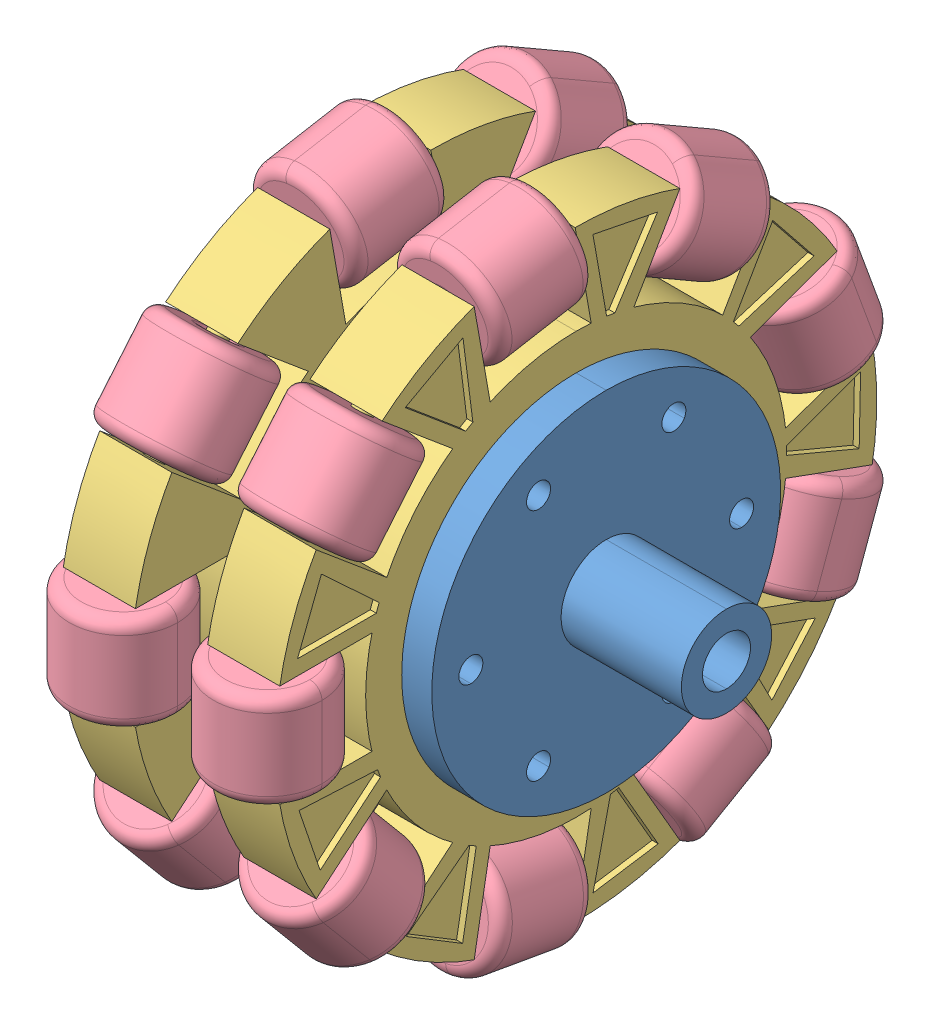
SolidWorks assembly omni wheel with hub, configuration Default. Lengths in mm.
Overall size (67.69 113.32 110.39).
26 component instances, 4 part files, 0 mates.
Components (placement in the parent):
- omni wheel with hub.igs-1: omni wheel with hub.igs [Default] at origin size (67.69 113.32 110.39)
  - Part1.1.2.3.2.igs-1: Part1.1.2.3.2.igs [Default] at (11 0 0) size (26.01 58.01 58.01)
  - Product1.1.2.igs-1: Product1.1.2.igs [Default] at origin size (49.36 113.32 110.39)
    - Part1.1.2.1.2.igs-1: Part1.1.2.1.2.igs [Default] at (-12 0 0) size (12.01 58.01 58.01)
    - Product1.1.2.6.igs-1: Product1.1.2.6.igs [Default] at origin size (25.36 112.48 110.39)
      - Part1.4.igs-1: Part1.4.igs [Default] at origin size (17.06 100.02 99.39)
      - Part1.1.3.igs-1: Part1.1.3.igs [Default] at (6 -8.0271 45.2675) x (0 1 0) z (0 0 1) size (16.01 18 18)
      - Part1.1.3.igs-2: Part1.1.3.igs [Default] at (6 22.9483 39.8366) x (0 0.766044 -0.642788) z (0.642788 0.492404 0.586824) size (16.01 18 18)
      - Part1.1.3.igs-3: Part1.1.3.igs [Default] at (6 43.1859 15.7657) x (0 0.173648 -0.984808) z (0.984808 0.17101 0.030154) size (16.01 18 18)
      - Part1.1.3.igs-4: Part1.1.3.igs [Default] at (6 43.3414 -15.4656) x (0 -0.5 -0.866025) z (0.866025 -0.433013 0.25) size (16.01 18 18)
      - Part1.1.3.igs-5: Part1.1.3.igs [Default] at (6 23.0254 -39.7921) x (0 -0.939693 -0.34202) z (0.34202 -0.321394 0.883022) size (16.01 18 18)
      - Part1.1.3.igs-6: Part1.1.3.igs [Default] at (6 -7.9394 -45.283) x (0 -0.939693 0.34202) z (-0.34202 0.321394 0.883022) size (16.01 18 18)
      - Part1.1.3.igs-7: Part1.1.3.igs [Default] at (6 -35.1893 -29.5854) x (0 -0.5 0.866025) z (-0.866025 0.433013 0.25) size (16.01 18 18)
      - Part1.1.3.igs-8: Part1.1.3.igs [Default] at (6 -45.9737 -0.0445) x (0 0.173648 0.984808) z (-0.984808 -0.17101 0.030154) size (16.01 18 18)
      - Part1.1.3.igs-9: Part1.1.3.igs [Default] at (6 -35.2465 29.5172) x (0 0.766044 0.642788) z (-0.642788 -0.492404 0.586824) size (16.01 18 18)
    - Product1.1.2.6.igs-2: Product1.1.2.6.igs [Default] at (-12 -0.8564 0) x (-1 0 0) z (0 0 1) size (25.36 112.48 110.39)
      - Part1.4.igs-1: Part1.4.igs [Default] at origin size (17.06 100.02 99.39)
      - Part1.1.3.igs-1: Part1.1.3.igs [Default] at (6 -8.0271 45.2675) x (0 1 0) z (0 0 1) size (16.01 18 18)
      - Part1.1.3.igs-2: Part1.1.3.igs [Default] at (6 22.9483 39.8366) x (0 0.766044 -0.642788) z (0.642788 0.492404 0.586824) size (16.01 18 18)
      - Part1.1.3.igs-3: Part1.1.3.igs [Default] at (6 43.1859 15.7657) x (0 0.173648 -0.984808) z (0.984808 0.17101 0.030154) size (16.01 18 18)
      - Part1.1.3.igs-4: Part1.1.3.igs [Default] at (6 43.3414 -15.4656) x (0 -0.5 -0.866025) z (0.866025 -0.433013 0.25) size (16.01 18 18)
      - Part1.1.3.igs-5: Part1.1.3.igs [Default] at (6 23.0254 -39.7921) x (0 -0.939693 -0.34202) z (0.34202 -0.321394 0.883022) size (16.01 18 18)
      - Part1.1.3.igs-6: Part1.1.3.igs [Default] at (6 -7.9394 -45.283) x (0 -0.939693 0.34202) z (-0.34202 0.321394 0.883022) size (16.01 18 18)
      - Part1.1.3.igs-7: Part1.1.3.igs [Default] at (6 -35.1893 -29.5854) x (0 -0.5 0.866025) z (-0.866025 0.433013 0.25) size (16.01 18 18)
      - Part1.1.3.igs-8: Part1.1.3.igs [Default] at (6 -45.9737 -0.0445) x (0 0.173648 0.984808) z (-0.984808 -0.17101 0.030154) size (16.01 18 18)
      - Part1.1.3.igs-9: Part1.1.3.igs [Default] at (6 -35.2465 29.5172) x (0 0.766044 0.642788) z (-0.642788 -0.492404 0.586824) size (16.01 18 18)
